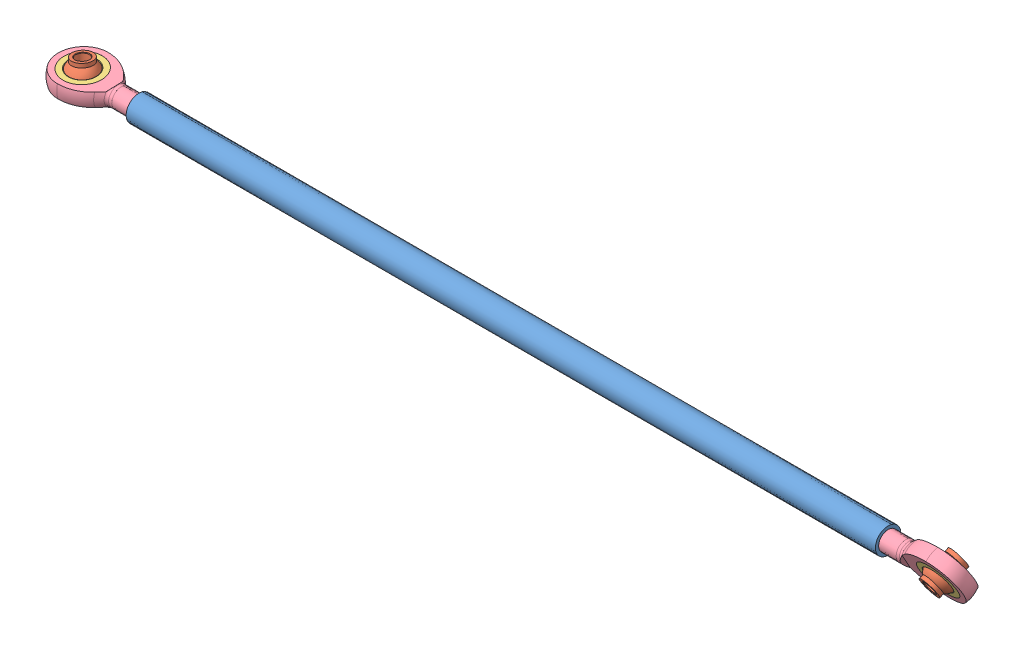
SolidWorks assembly Front Pull Rod, configuration Default. Lengths in mm.
Overall size (465.76 63.12 62.57).
9 component instances, 4 part files, 4 mates.
Components (placement in the parent):
- Front Pull Rod-1: Front Pull Rod [Default<As Machined>] at (-68.5436 206.4804 295.8455) size (373.02 12.7 12.7)
- HXAM-4T Rod End-1: HXAM-4T Rod End [Default] at (-96.3439 206.4804 295.8455) x (0.965627 0.087659 -0.244705) z (0.236655 0.092903 0.967142) size (69.2 35.42 44.66) (flexible)
  - HXAM-4T Ball-1: HXAM-4T Ball [Default] at (0 0 -49.2252) size (15.06 15.06 15.06)
  - HXAM-4T Sleeve-1: HXAM-4T Sleeve [Default] at (47.5332 -5.2923 11.6494) x (-0.247981 -0.108146 0.96271) z (-0.965627 0.107513 -0.236655) size (19.53 6.73 19.53)
  - HXAM-4T Housing-1: HXAM-4T Housing [Default] at (47.5332 -5.2923 11.6494) x (-0.247981 -0.108146 0.96271) z (-0.965627 0.107513 -0.236655) size (27.48 26.04 62.51)
- HXAM-4T Rod End-2: HXAM-4T Rod End [Default] at (332.2811 206.4804 295.8455) x (-0.980034 0.198827 -0.000973) z (-0.169188 -0.836493 -0.521206) size (68.56 33.24 38.87) (flexible)
  - HXAM-4T Ball-1: HXAM-4T Ball [Default] at (0 0 -49.2252) size (15.06 15.06 15.06)
  - HXAM-4T Sleeve-1: HXAM-4T Sleeve [Default] at (48.2424 -5.1412 8.3283) x (-0.173187 -0.030424 0.984419) z (-0.980034 0.104443 -0.169188) size (19.53 6.73 19.53)
  - HXAM-4T Housing-1: HXAM-4T Housing [Default] at (48.2424 -5.1412 8.3283) x (-0.173187 -0.030424 0.984419) z (-0.980034 0.104443 -0.169188) size (27.48 26.04 62.51)
Mates (geometry in assembly coordinates):
- Concentric1: concentric anti-aligned: cylinder of Front Pull Rod-1 through (304.4808 206.4804 295.8455) axis (-1 0 0) radius 6.35; cylinder of HXAM-4T Rod End-1/HXAM-4T Housing-1 through (-62.5098 206.4804 295.8455) axis (1 0 0) radius 4.7625
- Concentric2: concentric aligned: cylinder of Front Pull Rod-1 through (304.4808 206.4804 295.8455) axis (-1 0 0) radius 6.35; cylinder of ? through (298.4471 206.4804 295.8455) axis (-1 0 0) radius 4.7625
- Coincident1: coincident: point of Front Pull Rod-1; point of HXAM-4T Rod End-1/HXAM-4T Ball-1
- Coincident2: coincident: point of Front Pull Rod-1; point of HXAM-4T Rod End-2/HXAM-4T Ball-1
